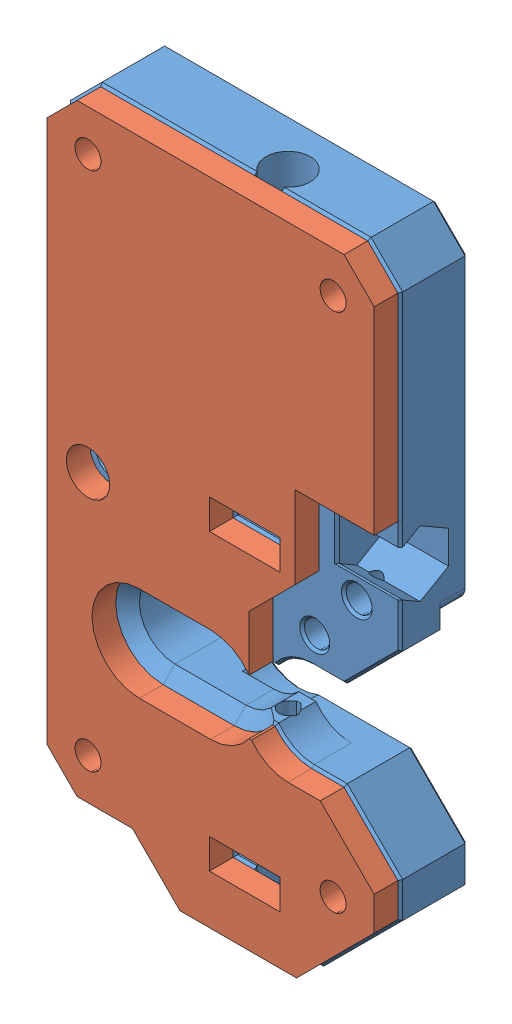
SolidWorks assembly Assem1, configuration Default. Lengths in mm.
Overall size (42 82.85 11.5).
2 component instances, 2 part files, 4 mates.
Components (placement in the parent):
- 1239.5-1: 1239.5 [Default] at (-43.8194 -0.1499 9.1746) size (42 82.85 8.5)
- 1239.5 Cover-1: 1239.5 Cover [Default] at (-43.8194 -0.1499 17.6746) size (41.4 82.25 3)
Mates (geometry in assembly coordinates):
- InPlace1: in place: plane of 1239.5-1 through (-34.0144 -0.1499 17.6746) normal (0 0 1); plane of ? through (0 0 17.6746) normal (0 0 1); moOrthogonalPlaneRef_w of 1239.5-1 through (-34.0144 -0.1499 17.6746) normal (0 0 1); plane of ? through (0 0 17.6746) normal (0 1 0); plane of 1239.5-1 through (-34.0144 -0.1499 17.6746) normal (0 0 1); plane of ? through (0 0 17.6746) normal (1 0 0); plane of 1239.5-1 through (-34.0144 -0.1499 17.6746) normal (0 0 1); unknown of 1239.5 Cover-1
- Coincident1: coincident aligned: plane of 1239.5-1; plane of 1239.5 Cover-1
- Coincident2: coincident aligned: moOrthogonalPlaneRef_w of 1239.5-1 through (-43.8194 -0.1499 17.6746) normal (0 1 0); plane of 1239.5 Cover-1 through (-43.8194 -0.1499 17.6746) normal (0 1 0)
- Coincident3: coincident anti-aligned: moOrthogonalPlaneRef_w of 1239.5-1 through (-43.8194 -0.1499 17.6746) normal (-1 0 0); plane of 1239.5 Cover-1 through (-43.8194 -0.1499 17.6746) normal (1 0 0)
